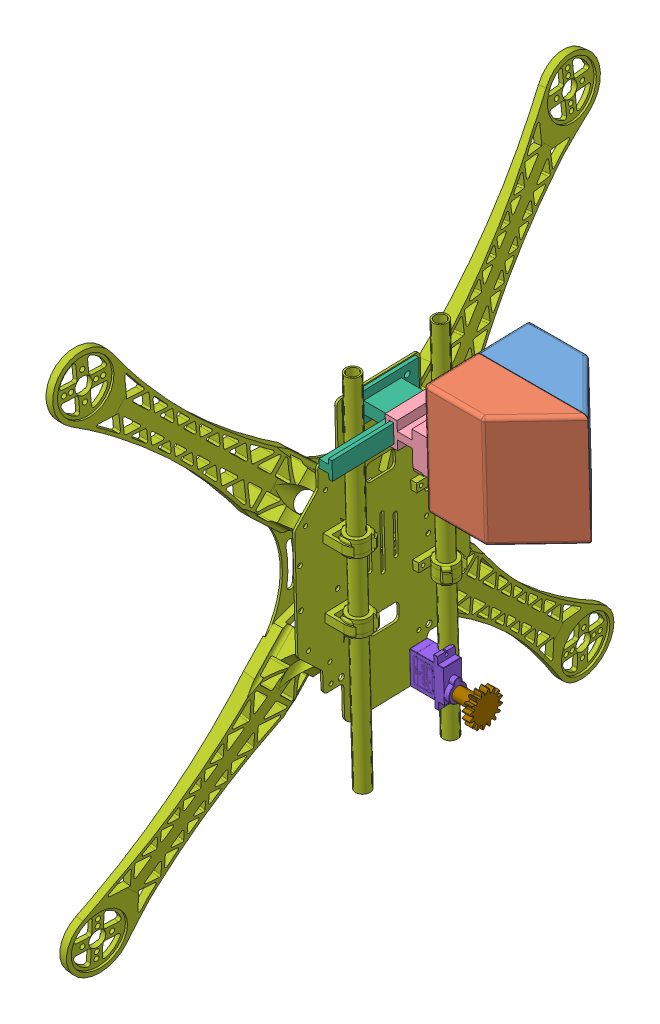
SolidWorks assembly Scoop Assembly, configuration Default. Lengths in mm.
Overall size (168.06 384.86 384.86).
11 component instances, 11 part files, 27 mates.
Components (placement in the parent):
- scoop-1: scoop [Default] at (243.9248 208.3179 -30.6702) x (0 0.999607 0.028016) z (0 -0.028016 0.999607) size (77.47 76.56 35.92)
- scoop_rack final-1: scoop_rack final [Default] at (304.8996 223.0661 90.3423) x (0 -0.999607 -0.028016) z (0 0.028016 -0.999607) size (77.47 87.99 49.96)
- ping pong ball-1: ping pong ball [Default] at (249.5406 218.1648 11.2824) size (39.88 39.88 39.88)
- rack gear-1: rack gear [Default] at (304.8996 223.0661 90.3423) x (0 -0.999607 -0.028016) z (0 0.028016 -0.999607) size (25.73 29.72 78.37)
- no rack scoop rail-1: no rack scoop rail [Default] at (304.8996 224.011 56.6165) x (0 -0.999607 -0.028016) z (0 0.028016 -0.999607) size (28.02 29.72 47.42)
- Master scoop rail-1: Master scoop rail [Default] at (170.1048 204.4116 20.9217) x (0 0.028016 -0.999607) z (0 -0.999607 -0.028016) size (122 28.1 20)
- S500 Frame-1: S500 Frame [Default] at (170.1048 112.6976 18.3512) x (0 -0.999607 -0.028016) z (-1 0 0) size (374.52 374.52 61.06)
- User Library-SG90-3-1: User Library-SG90-3 [Default] at (186.931 28.9063 -38.5791) x (0 -0.999607 -0.028016) z (0 -0.028016 0.999607) size (32.36 29.6 12.25)
- Drone Legs-1: Drone Legs [Default] at (326.6818 235.7638 105.0383) x (-0.251398 0.003548 0.967877) z (0 -0.999993 0.003666) size (19.56 171.15 242.57) (hidden)
- Drone Legs Right-1: Drone Legs Right [Default] at (326.6818 232.8473 -78.5991) x (0.251398 0.059733 0.966039) z (0 -0.998094 0.061715) size (19.56 171.15 242.57) (hidden)
- Scoop Spur gear-3: Scoop Spur gear [Inch - Spur gear 20DP 16T 20PA .2FW ---S16N3.0H2.0L0.0787N] at (215.9848 24.4601 -6.5307) x (-1 0 0) z (0 0.911912 0.410386) size (19.05 22.53 22.53)
Mates (geometry in assembly coordinates):
- Parallel6: parallel anti-aligned: plane of scoop-1 through (298.8958 293.0028 7.6384) normal (0 -0.028016 0.999607); plane of scoop_rack final-1 through (298.8958 121.6101 3.1928) normal (0 0.028016 -0.999607)
- Coincident19: coincident aligned: plane of scoop-1 through (243.9248 169.5981 -31.7554) normal (0 -0.999607 -0.028016); plane of scoop_rack final-1 through (243.9248 167.5753 40.4162) normal (0 -0.999607 -0.028016)
- Coincident20: coincident aligned: plane of scoop-1 through (222.3348 208.3179 -30.6702) normal (-1 0 0); plane of scoop_rack final-1 through (222.3348 206.2951 41.5014) normal (-1 0 0)
- Concentric1: concentric anti-aligned: circle of scoop_rack final-1; circle of rack gear-1
- Concentric2: concentric anti-aligned: circle of scoop_rack final-1; circle of rack gear-1
- Coincident23: coincident anti-aligned: plane of scoop_rack final-1 through (222.3348 206.2951 41.5014) normal (-1 0 0); plane of rack gear-1 through (222.3348 223.0661 90.3423) normal (1 0 0)
- Concentric3: concentric aligned: circle of scoop-1; circle of no rack scoop rail-1
- Concentric4: concentric aligned: circle of scoop-1; circle of no rack scoop rail-1
- Coincident26: coincident anti-aligned: plane of scoop-1 through (222.3348 208.3179 -30.6702) normal (-1 0 0); plane of no rack scoop rail-1 through (222.3348 224.011 56.6165) normal (1 0 0)
- Parallel7: parallel aligned: plane of rack gear-1 through (217.2548 186.6652 38.4103) normal (0 -0.028016 0.999607); plane of Master scoop rail-1 through (195.6648 197.4387 80.7498) normal (0 -0.028016 0.999607)
- Coincident28: coincident anti-aligned: plane of no rack scoop rail-1 through (198.2048 224.011 56.6165) normal (-1 0 0); plane of Master scoop rail-1 through (198.2048 204.4116 20.9217) normal (1 0 0)
- Distance1: distance = 0.254 mm anti-aligned: plane of Master scoop rail-1 through (198.2048 197.373 -39.2992) normal (0 -0.999607 -0.028016); plane of no rack scoop rail-1 through (192.6168 195.8797 4.9163) normal (0 0.999607 0.028016)
- Concentric5: concentric aligned: circle of Master scoop rail-1; circle of S500 Frame-1
- Parallel8: parallel aligned: plane of Master scoop rail-1 through (172.6448 211.9087 21.1318) normal (0 0.999607 0.028016); plane of S500 Frame-1 through (170.1048 211.8599 49.6416) normal (0 0.999607 0.028016)
- Coincident31: coincident anti-aligned: plane of Master scoop rail-1 through (170.1048 204.4116 20.9217) normal (-1 0 0); plane of S500 Frame-1 through (170.1048 115.1967 18.4212) normal (1 0 0)
- Coincident33: coincident anti-aligned: plane of S500 Frame-1 through (170.1048 115.1967 18.4212) normal (1 0 0); plane of Drone Legs-1 through (170.1048 -6.9907 55.1551) normal (-1 0 0)
- Parallel9: parallel aligned: plane of S500 Frame-1 through (168.6048 115.1967 18.4212) normal (-1 0 0); plane of Drone Legs-1 through (170.1048 -6.9907 55.1551) normal (-1 0 0)
- Lock1: lock: unknown of S500 Frame-1; unknown of Drone Legs-1
- Parallel10: parallel aligned: plane of S500 Frame-1 through (168.6048 115.1967 18.4212) normal (-1 0 0); plane of Drone Legs Right-1 through (170.1048 -7.374 -33.1212) normal (-1 0 0)
- Coincident35: coincident anti-aligned: plane of S500 Frame-1 through (170.1048 115.1967 18.4212) normal (1 0 0); plane of Drone Legs Right-1 through (170.1048 -7.374 -33.1212) normal (-1 0 0)
- Tangent4: tangent: line of S500 Frame-1 through (170.1048 150.9672 -39.5994) axis (0 -0.999607 -0.028016); curve of Drone Legs Right-1
- Lock2: lock: unknown of S500 Frame-1; unknown of Drone Legs Right-1
- Coincident36: coincident aligned: plane of rack gear-1 through (210.9048 183.9868 70.979) normal (-1 0 0); plane of Scoop Spur gear-3 through (210.9048 24.4601 -6.5307) normal (-1 0 0)
- Coincident38: coincident anti-aligned: plane of User Library-SG90-3-1 through (170.1048 18.1916 -0.604) normal (-1 0 0); plane of S500 Frame-1 through (170.1048 115.1967 18.4212) normal (1 0 0)
- Coincident39: coincident aligned: plane of S500 Frame-1 through (170.1048 18.5334 -12.7992) normal (0 -0.999607 -0.028016); plane of User Library-SG90-3-1 through (186.9048 18.1916 -0.604) normal (0 -0.999607 -0.028016)
- Coincident40: coincident aligned: plane of S500 Frame-1 through (170.1048 44.5232 -12.0708) normal (0 0.028016 -0.999607); plane of User Library-SG90-3-1 through (193.4048 18.5334 -12.7992) normal (0 0.028016 -0.999607)
- Concentric6: concentric anti-aligned: circle of User Library-SG90-3-1; circle of Scoop Spur gear-3
